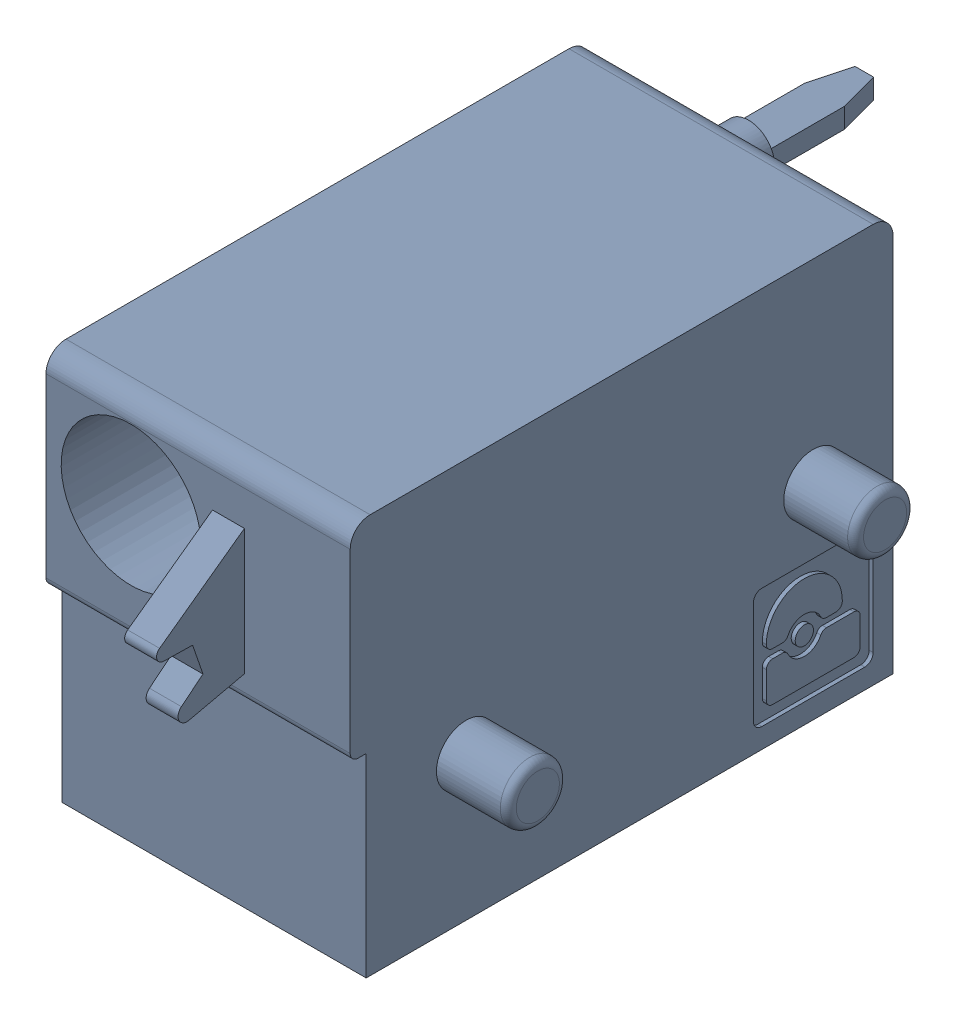
SolidWorks assembly J86, configuration Default. Lengths in mm.
Overall size (9.42 10 19.2).
2 component instances, 1 part files, 0 mates.
Components (placement in the parent):
- 1790377-1: 1790377 [Default] at (245.7451 -7.6199 0) x (0 1 0) z (1 0 0) size (10 19.2 9.42)
  - ffkdsa-v2-7.62-1: ffkdsa-v2-7.62 [Default] at (-23.7414 -38.158 -5.08) x (0 -1 0) z (0 0 1) size (19.2 10 9.42)
